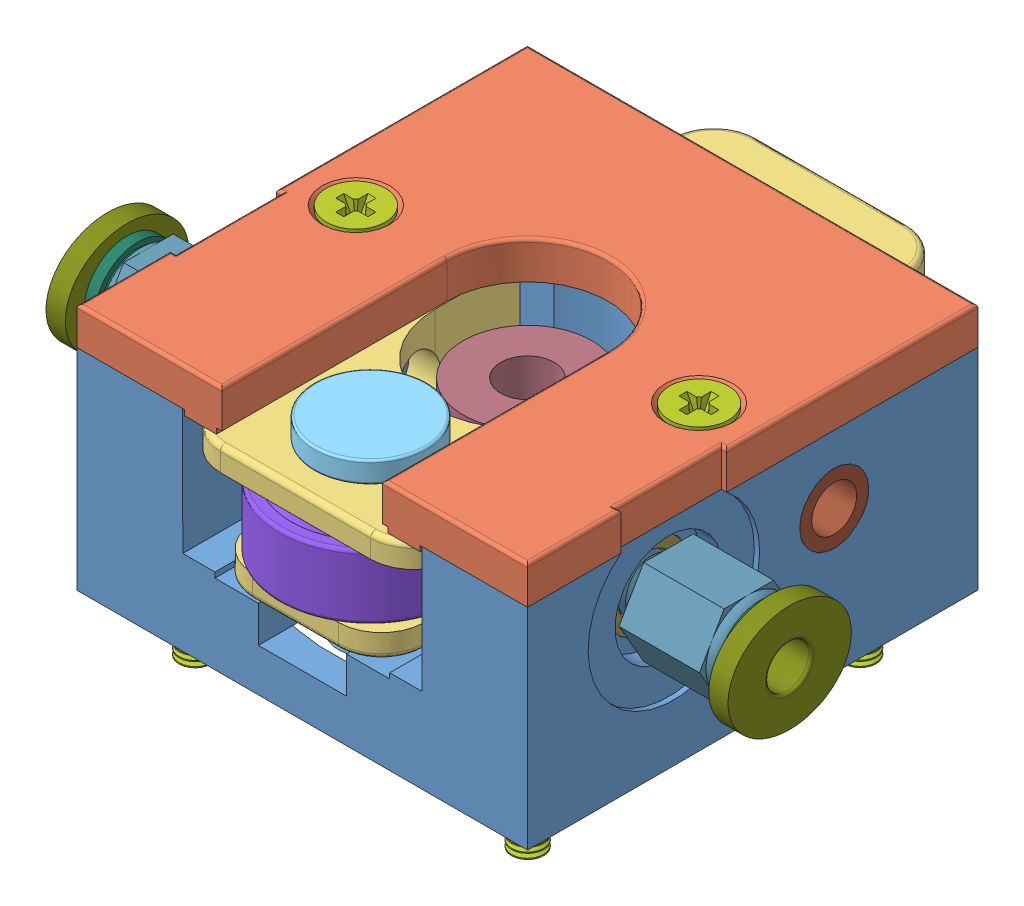
SolidWorks assembly Extrusor, configuration Predeterminado. Lengths in mm.
Overall size (63.61 28.53 52.68).
33 component instances, 18 part files, 56 mates.
Components (placement in the parent):
- Basse-1: Basse [Predeterminado] at (-0.0153 0.0026 -2.9939) x (1 0.000641 0) z (0 0 1) size (42 21.5 42)
- Tapa-1: Tapa [Predeterminado] at (-0.0176 3.5026 -2.9939) x (1 0.000641 0) z (0 0 1) size (42 4 42)
- Empujador-1: Empujador [Predeterminado] at (-0.015 -0.5974 -6.3697) x (-1 -0.000641 0) z (0 0 -1) size (22 11 50)
- Muelle-1: Muelle [Default] at (-3.9239 -5.9972 -23.5215) x (0.99759 0.06938 0.000016) z (0.00304 -0.043937 0.99903) size (6.02 6.09 11.75)
- Muelle-2: Muelle [Default] at (3.4631 -5.9484 -22.8222) x (0.444628 0.895715 0) z (0.039448 -0.019582 0.99903) size (6.02 6.09 11.75)
- Eje Empujador-1: Eje Empujador [Predeterminado] at (-3.0053 -15.5994 11.6303) x (1 0.000641 0) z (0.000641 -1 0) size (10.5 10.5 17.5)
- slotted set screw dog point_jis-1: slotted set screw dog point_jis [JIS B 1117 Long dog point M4 x 12--S] at (-4.0114 -6.1 -32.5466) x (0 0 1) z (0.594696 0.803951 0) size (12 4 4)
- slotted set screw dog point_jis-2: slotted set screw dog point_jis [JIS B 1117 Long dog point M4 x 12--S] at (3.9886 -6.0949 -32.2333) x (0 0 1) z (-0.953222 0.302272 0) size (12 4 4)
- countersunk flat head cross recess screw_iso-1: countersunk flat head cross recess screw_iso [ISO 7046-1 - M3 x 10 - Z --- 10S] at (-16.0176 3.4923 -2.9939) x (0.000641 -1 0) z (0 0 1) size (10 5.5 5.5)
- countersunk flat head cross recess screw_iso-2: countersunk flat head cross recess screw_iso [ISO 7046-1 - M3 x 10 - Z --- 10S] at (15.9824 3.5128 -2.9939) x (0.000641 -1 0) z (0 0 1) size (10 5.5 5.5)
- angular contact ball bearing_68_iso-2: angular contact ball bearing_68_iso [ISO 15 ABB - 106 - 8,SI,NC,8_68] at (-0.0114 -6.0974 11.6303) x (0.000641 -1 0) z (0 0 1) size (6 17 17)
- lock washer for shafts_din-1: lock washer for shafts_din [Lock washer DIN 6799 - 5] at (-0.0079 -11.5974 11.6303) x (1 0.000641 0) z (-0.000641 1 0) size (11.3 9.55 0.7)
- Inserto M3-1: Inserto M3 [Predeterminado] at (-16.0089 -10.0077 -2.9939) x (0.361954 0.000232 0.932196) z (-0.000641 1 0) size (4.5 4.5 10)
- Inserto M3-2: Inserto M3 [Predeterminado] at (15.9911 -9.9872 -2.9939) x (1 0.000641 0) z (-0.000641 1 0) size (4.5 4.5 10)
- Inserto M5-1: Inserto M5 [Predeterminado] at (20.9887 -6.284 -10.5939) x (0 0 1) z (-1 -0.000641 0) size (6.5 6.5 9.85)
- Inserto M5-2: Inserto M5 [Predeterminado] at (-21.0113 -6.3109 -10.5939) x (0 0 -1) z (1 0.000641 0) size (6.5 6.5 9.85)
- Inserto 1_4-28-1: Inserto 1_4-28 [Predeterminado] at (-11.1613 -6.3046 4.3561) x (0 0 1) z (-1 -0.000641 0) size (7.7 7.7 7.35)
- Inserto 1_4-28-2: Inserto 1_4-28 [Predeterminado] at (18.4887 -6.2856 4.3561) x (0 0 1) z (-1 -0.000641 0) size (7.7 7.7 7.35)
- Inserto M5-3: Inserto M5 [D8] at (4 -6.1 -31.3697) size (6.5 6.5 8)
- Inserto M5-4: Inserto M5 [D8] at (-4.0114 -6.1 -31.3697) size (6.5 6.5 8)
- nema17-1: nema17 [Défaut] at (-0.0028 -19.5974 -2.9939) x (1 0.000641 0) z (0.000641 -1 0) size (42 42 71) (hidden)
- Rodillo-1: Rodillo [Predeterminado] at (-0.007 -12.9474 -2.9939) x (0.923728 0.000593 0.383049) z (-0.000641 1 0) size (12 12 10.5)
- AW6  Fitting-1: AW6  Fitting [Défaut] at (-14.0113 -6.3064 4.3561) x (0 0 1) z (-1 -0.000641 0) size (9.24 8 15.43)
- Easy realise fitting part1-1: Easy realise fitting part1 [Default] at (-29.0113 -6.316 4.3561) x (0 0 1) z (-0.000641 1 0) size (8 6.5 8)
- Easy realise fitting part2-1: Easy realise fitting part2 [Default] at (-31.8113 -6.3178 4.3561) x (0 0 1) z (-0.000641 1 0) size (11.5 7.3 10)
- AW6  Fitting-2: AW6  Fitting [Défaut] at (13.9887 -6.2885 4.3561) x (0 0 -1) z (1 0.000641 0) size (9.24 8 15.43)
- Easy realise fitting part1-2: Easy realise fitting part1 [Default] at (28.9887 -6.2788 4.3561) x (0 0 -1) z (-0.000641 1 0) size (8 6.5 8)
- Easy realise fitting part2-2: Easy realise fitting part2 [Default] at (31.7887 -6.277 4.3561) x (0 0 -1) z (-0.000641 1 0) size (11.5 7.3 10)
- countersunk flat head cross recess screw_iso-7: countersunk flat head cross recess screw_iso [ISO 7046-1 - M3 x 25 - Z --- 25S] at (-15.5153 -0.0074 -18.4939) x (0.000641 -1 0) z (0 0 1) size (25 5.5 5.5)
- countersunk flat head cross recess screw_iso-8: countersunk flat head cross recess screw_iso [ISO 7046-1 - M3 x 25 - Z --- 25S] at (15.4846 0.0125 -18.4939) x (0.000641 -1 0) z (0 0 1) size (25 5.5 5.5)
- countersunk flat head cross recess screw_iso-9: countersunk flat head cross recess screw_iso [ISO 7046-1 - M3 x 25 - Z --- 25S] at (15.4846 0.0125 12.5061) x (0.000641 -1 0) z (0 0 1) size (25 5.5 5.5)
- countersunk flat head cross recess screw_iso-10: countersunk flat head cross recess screw_iso [ISO 7046-1 - M3 x 25 - Z --- 25S] at (-15.5153 -0.0074 12.5061) x (0.000641 -1 0) z (0 0 1) size (25 5.5 5.5)
- socket set screw cone point_iso-1: socket set screw cone point_iso [ISO 4027 - M3 x 4-N] at (2.239 -10.146 -8.4146) x (-0.383049 -0.000246 0.923728) z (-0.923728 0.000368 -0.383049) size (4 3 3)
Mates (geometry in assembly coordinates):
- Concéntrica1: concentric anti-aligned: cylinder of Basse-1 through (15.9807 6.2354 -2.9939) axis (0.000641 -1 0) radius 2.2; cylinder of Tapa-1 through (15.9824 3.5128 -2.9939) axis (-0.000641 1 0) radius 1.7
- Concéntrica2: concentric anti-aligned: cylinder of Basse-1 through (-16.0193 6.2148 -2.9939) axis (0.000641 -1 0) radius 2.2; cylinder of Tapa-1 through (-16.0176 3.4923 -2.9939) axis (-0.000641 1 0) radius 1.7
- Coincidente1: coincident anti-aligned: plane of Basse-1 through (-0.0153 0.0026 -2.9939) normal (-0.000641 1 0); plane of Tapa-1 through (-0.0153 0.0026 -2.9939) normal (0.000641 -1 0)
- Ancho1: width anti-aligned: plane of Basse-1 through (-11.1578 -11.7046 -23.9939) normal (1 0.000641 0); plane of Empujador-1 through (11.1422 -11.6903 -23.9939) normal (-1 -0.000641 0); plane of Basse-1 through (-11.0079 -11.6045 14.6303) normal (-1 -0.000641 0); plane of Empujador-1 through (10.9921 -11.5904 14.6303) normal (1 0.000641 0)
- Tangente3: tangent aligned: plane of Basse-1 through (3.9886 -6.1949 -12.2939) normal (0 0 -1); face of Muelle-2
- Tangente4: tangent anti-aligned: cylinder of Basse-1 through (3.9886 -6.1949 -12.2939) axis (0 0 -1) radius 2.7; edge_curve of Muelle-2
- Tangente5: tangent anti-aligned: plane of Basse-1 through (-4.0114 -6.2 -12.2939) normal (0 0 -1); edge_curve of Muelle-1
- Tangente6: tangent aligned: cylinder of Basse-1 through (-4.0114 -6.2 -12.2939) axis (0 0 -1) radius 2.7; edge_curve of Muelle-1
- Concéntrica3: concentric aligned: cylinder of Empujador-1 through (-0.015 -0.5974 11.6303) axis (-0.000641 1 0) radius 3; cylinder of Eje Empujador-1 through (-0.0166 1.9026 11.6303) axis (-0.000641 1 0) radius 3
- Concéntrica4: concentric aligned: cylinder of Empujador-1 through (-4.0114 -6.1 -31.3697) axis (0 0 -1) radius 3.2; cylinder of slotted set screw dog point_jis-1 through (-4.0114 -6.1 -45.2466) axis (0 0 -1) radius 2
- Concéntrica5: concentric aligned: cylinder of Empujador-1 through (3.9886 -6.0949 -31.3697) axis (0 0 -1) radius 3.2; cylinder of slotted set screw dog point_jis-2 through (3.9886 -6.0949 -44.9333) axis (0 0 -1) radius 2
- Concéntrica6: concentric anti-aligned: cylinder of Eje Empujador-1 through (-0.0166 1.9026 11.6303) axis (-0.000641 1 0) radius 3; cylinder of ? through (0 14.4375 11.0262) axis (0 -1 0) radius 3
- Ancho2: width anti-aligned: plane of Empujador-1 through (10.9907 -9.3904 19.6936) normal (-0.000641 1 0); plane of Empujador-1 through (10.9864 -2.7904 0.3303) normal (0.000641 -1 0); plane of ? through (6.3362 -9.2 4.3559) normal (0 -1 0); plane of ? through (5.6302 -3.2 5.099) normal (0 1 0)
- Coincidente5: coincident aligned: cone of Tapa-1 through (-16.0176 3.4923 -2.9939) axis (0.000641 -1 0); cone of countersunk flat head cross recess screw_iso-1 through (-16.0173 3.0923 -2.9939) axis (0.000641 -1 0)
- Coincidente6: coincident aligned: cone of Tapa-1 through (15.9824 3.5128 -2.9939) axis (0.000641 -1 0); cone of countersunk flat head cross recess screw_iso-2 through (15.9827 3.1128 -2.9939) axis (0.000641 -1 0)
- Concéntrica7: concentric anti-aligned: cylinder of Eje Empujador-1 through (-0.0166 1.9026 11.6303) axis (-0.000641 1 0) radius 3; cylinder of angular contact ball bearing_68_iso-2 through (-0.0247 14.5401 11.6303) axis (0.000641 -1 0) radius 3
- Ancho3: width anti-aligned: plane of Empujador-1 through (10.9907 -9.3904 19.6936) normal (-0.000641 1 0); plane of angular contact ball bearing_68_iso-2 through (10.9864 -2.7904 0.3303) normal (0.000641 -1 0); plane of Empujador-1 through (8.1905 -9.0922 11.6303) normal (0.000641 -1 0); plane of angular contact ball bearing_68_iso-2 through (7.3616 -3.0927 11.6303) normal (-0.000641 1 0)
- Ancho4: width aligned: plane of Empujador-1 through (6.985 -0.593 -27.3697) normal (-0.000641 1 0); plane of Empujador-1 through (6.9921 -11.5929 -27.3697) normal (0.000641 -1 0); plane of Basse-1 through (-0.0078 -11.6974 -2.9939) normal (-0.000641 1 0); plane of Tapa-1 through (-0.015 -0.4974 -2.9939) normal (0.000641 -1 0)
- Concéntrica8: concentric aligned: cylinder of Eje Empujador-1 through (-0.0166 1.9026 11.6303) axis (-0.000641 1 0) radius 2.5; cylinder of lock washer for shafts_din-1 through (-0.0075 -12.2974 11.6303) axis (-0.000641 1 0) radius 2.5
- Coincidente7: coincident anti-aligned: plane of Eje Empujador-1 through (-3.0079 -11.5994 11.6303) normal (0.000641 -1 0); plane of lock washer for shafts_din-1 through (-0.0079 -11.5974 11.6303) normal (-0.000641 1 0)
- Concéntrica9: concentric anti-aligned: cylinder of Basse-1 through (-16.0193 6.2148 -2.9939) axis (0.000641 -1 0) radius 2.2; cylinder of Inserto M3-1 through (-16.0153 -0.0077 -2.9939) axis (-0.000641 1 0) radius 1.25
- Coincidente8: coincident aligned: plane of Basse-1 through (-0.0153 0.0026 -2.9939) normal (-0.000641 1 0); plane of Inserto M3-1 through (-16.0153 -0.0077 -2.9939) normal (-0.000641 1 0)
- Concéntrica10: concentric anti-aligned: cylinder of Basse-1 through (15.9807 6.2354 -2.9939) axis (0.000641 -1 0) radius 2.2; cylinder of Inserto M3-2 through (15.9846 0.0128 -2.9939) axis (-0.000641 1 0) radius 1.25
- Coincidente9: coincident aligned: plane of Basse-1 through (-0.0153 0.0026 -2.9939) normal (-0.000641 1 0); plane of Inserto M3-2 through (15.9846 0.0128 -2.9939) normal (-0.000641 1 0)
- Concéntrica11: concentric anti-aligned: cylinder of Basse-1 through (20.9887 -6.284 -10.5939) axis (1 0.000641 0) radius 3.2; cylinder of Inserto M5-1 through (11.1387 -6.2903 -10.5939) axis (-1 -0.000641 0) radius 2.1
- Coincidente10: coincident aligned: plane of Basse-1 through (20.9972 -19.584 -23.9939) normal (1 0.000641 0); plane of Inserto M5-1 through (20.9887 -6.284 -10.5939) normal (1 0.000641 0)
- Concéntrica12: concentric anti-aligned: cylinder of Basse-1 through (-21.0113 -6.3109 -10.5939) axis (-1 -0.000641 0) radius 3.2; cylinder of Inserto M5-2 through (-11.1613 -6.3046 -10.5939) axis (1 0.000641 0) radius 2.1
- Coincidente11: coincident aligned: plane of Basse-1 through (-21.0028 -19.6109 -23.9939) normal (-1 -0.000641 0); plane of Inserto M5-2 through (-21.0113 -6.3109 -10.5939) normal (-1 -0.000641 0)
- Concéntrica13: concentric anti-aligned: cylinder of Basse-1 through (18.4887 -6.2856 4.3561) axis (1 0.000641 0) radius 3.8; cylinder of Inserto 1_4-28-1 through (-18.5113 -6.3093 4.3561) axis (-1 -0.000641 0) radius 2.7051
- Coincidente12: coincident aligned: plane of Basse-1 through (-18.5113 -6.3093 4.3561) normal (-1 -0.000641 0); plane of Inserto 1_4-28-1 through (-18.5113 -6.3093 4.3561) normal (-1 -0.000641 0)
- Concéntrica14: concentric anti-aligned: cylinder of Basse-1 through (18.4887 -6.2856 4.3561) axis (1 0.000641 0) radius 3.8; cylinder of Inserto 1_4-28-2 through (11.1387 -6.2903 4.3561) axis (-1 -0.000641 0) radius 2.7051
- Coincidente13: coincident aligned: plane of Basse-1 through (18.4887 -6.2856 4.3561) normal (1 0.000641 0); plane of Inserto 1_4-28-2 through (18.4887 -6.2856 4.3561) normal (1 0.000641 0)
- Concéntrica16: concentric anti-aligned: cylinder of Empujador-1 through (-4.0114 -6.1 -31.3697) axis (0 0 -1) radius 3.2; cylinder of Inserto M5-4 through (-4.0114 -6.1 -23.3697) axis (0 0 1) radius 2.1
- Coincidente15: coincident aligned: plane of Empujador-1 through (6.9921 -11.5929 -31.3697) normal (0 0 -1); plane of Inserto M5-4 through (-4.0114 -6.1 -31.3697) normal (0 0 -1)
- Coincidente16: coincident aligned: plane of Empujador-1 through (6.9921 -11.5929 -27.3697) normal (0.000641 -1 0); plane of Eje Empujador-1 through (-3.0079 -11.5994 11.6303) normal (0.000641 -1 0)
- Coincidente18: coincident anti-aligned: plane of Basse-1 through (-0.0028 -19.5974 -2.9939) normal (0.000641 -1 0); plane of nema17-1 through (-0.0028 -19.5974 -2.9939) normal (-0.000641 1 0)
- Concéntrica18: concentric aligned: cylinder of Basse-1 through (-0.0053 -15.5974 -2.9939) axis (0.000641 -1 0) radius 18.25; cylinder of nema17-1 through (-0.0041 -17.5974 -2.9939) axis (0.000641 -1 0) radius 11
- Concéntrica19: concentric aligned: cylinder of nema17-1 through (-0.0182 4.4026 -2.9939) axis (0.000641 -1 0) radius 2.5; cylinder of Rodillo-1 through (-0.0138 -2.4474 -2.9939) axis (0.000641 -1 0) radius 2.5
- Ancho5: width anti-aligned: plane of Rodillo-1 through (5.5317 -7.3439 -0.6956) normal (-0.000641 1 0); plane of angular contact ball bearing_68_iso-2 through (5.2992 -4.844 -0.7914) normal (0.000641 -1 0); plane of Rodillo-1 through (8.1905 -9.0922 11.6303) normal (0.000641 -1 0); plane of angular contact ball bearing_68_iso-2 through (7.3616 -3.0927 11.6303) normal (-0.000641 1 0)
- Concéntrica20: concentric aligned: cylinder of AW6  Fitting-1 through (-24.0113 -6.3128 4.3561) axis (-1 -0.000641 0) radius 3; cylinder of Easy realise fitting part1-1 through (-23.5113 -6.3125 4.3561) axis (-1 -0.000641 0) radius 3.5
- Coincidente19: coincident anti-aligned: circle of AW6  Fitting-1; plane of Easy realise fitting part1-1 through (-29.0113 -6.316 4.3561) normal (1 0.000641 0)
- Concéntrica21: concentric anti-aligned: cylinder of Easy realise fitting part1-1 through (-30.0113 -6.3167 4.3561) axis (1 0.000641 0) radius 2.75; cylinder of Easy realise fitting part2-1 through (-24.5113 -6.3132 4.3561) axis (-1 -0.000641 0) radius 2.75
- Coincidente20: coincident anti-aligned: plane of Easy realise fitting part1-1 through (-30.0113 -6.3167 4.3561) normal (-1 -0.000641 0); plane of Easy realise fitting part2-1 through (-30.0113 -6.3167 4.3561) normal (1 0.000641 0)
- Coincidente21: coincident anti-aligned: plane of Basse-1 through (-20.5113 -6.3106 4.3561) normal (-1 -0.000641 0); plane of AW6  Fitting-1 through (-20.5113 -6.3106 4.3561) normal (1 0.000641 0)
- Concéntrica23: concentric anti-aligned: cylinder of Inserto 1_4-28-1 through (-18.5113 -6.3093 4.3561) axis (-1 -0.000641 0) radius 2.7051; cylinder of Easy realise fitting part2-1 through (-31.8113 -6.3178 4.3561) axis (1 0.000641 0) radius 2
- Concéntrica24: concentric aligned: cylinder of AW6  Fitting-2 through (23.9887 -6.282 4.3561) axis (1 0.000641 0) radius 3; cylinder of Easy realise fitting part1-2 through (23.4887 -6.2824 4.3561) axis (1 0.000641 0) radius 3.5
- Coincidente22: coincident anti-aligned: circle of AW6  Fitting-2; plane of Easy realise fitting part1-2 through (28.9887 -6.2788 4.3561) normal (-1 -0.000641 0)
- Concéntrica25: concentric anti-aligned: cylinder of Easy realise fitting part1-2 through (29.9887 -6.2782 4.3561) axis (-1 -0.000641 0) radius 2.75; cylinder of Easy realise fitting part2-2 through (24.4887 -6.2817 4.3561) axis (1 0.000641 0) radius 2.75
- Coincidente23: coincident anti-aligned: plane of Easy realise fitting part1-2 through (29.9887 -6.2782 4.3561) normal (1 0.000641 0); plane of Easy realise fitting part2-2 through (29.9887 -6.2782 4.3561) normal (-1 -0.000641 0)
- Coincidente24: coincident anti-aligned: plane of Basse-1 through (20.4887 -6.2843 4.3561) normal (1 0.000641 0); plane of AW6  Fitting-2 through (20.4887 -6.2843 4.3561) normal (-1 -0.000641 0)
- Concéntrica26: concentric aligned: cylinder of Inserto 1_4-28-2 through (11.1387 -6.2903 4.3561) axis (-1 -0.000641 0) radius 2.7051; cylinder of Easy realise fitting part2-2 through (31.7887 -6.277 4.3561) axis (-1 -0.000641 0) radius 2
- Coincidente29: coincident aligned: cone of Basse-1 through (-15.5153 -0.0074 -18.4939) axis (0.000641 -1 0); cone of countersunk flat head cross recess screw_iso-7 through (-15.5151 -0.4074 -18.4939) axis (0.000641 -1 0)
- Coincidente30: coincident aligned: cone of Basse-1 through (15.4846 0.0125 -18.4939) axis (0.000641 -1 0); cone of countersunk flat head cross recess screw_iso-8 through (15.4849 -0.3875 -18.4939) axis (0.000641 -1 0)
- Coincidente31: coincident aligned: cone of Basse-1 through (15.4846 0.0125 12.5061) axis (0.000641 -1 0); cone of countersunk flat head cross recess screw_iso-9 through (15.4849 -0.3875 12.5061) axis (0.000641 -1 0)
- Coincidente32: coincident aligned: cone of Basse-1 through (-15.5153 -0.0074 12.5061) axis (0.000641 -1 0); cone of countersunk flat head cross recess screw_iso-10 through (-15.5151 -0.4074 12.5061) axis (0.000641 -1 0)
- Concéntrica281: concentric aligned: cylinder of Rodillo-1 through (2.2895 -10.146 -8.5363) axis (0.383049 0.000246 -0.923728) radius 1.25; cylinder of socket set screw cone point_iso-1 through (7.1037 -10.1429 -20.146) axis (0.383049 0.000246 -0.923728) radius 1.5
